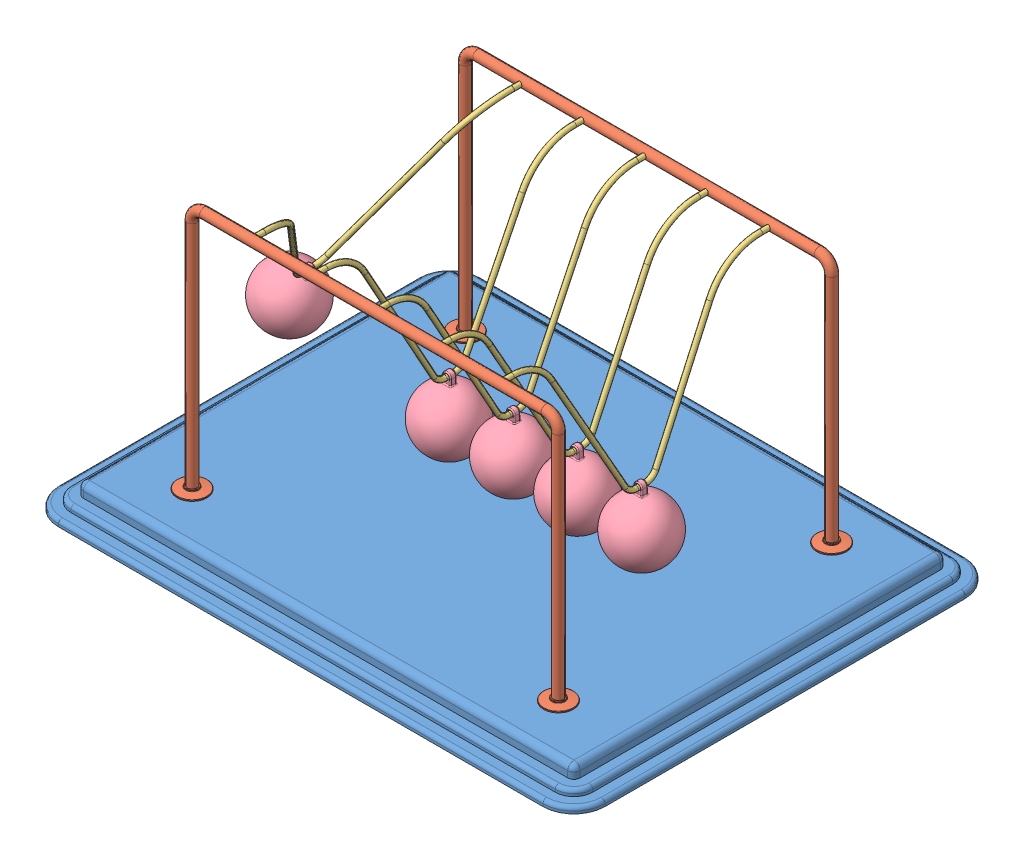
SolidWorks assembly Newtons Cradle NewtonsCradle 0254, configuration Default. Lengths in mm.
Overall size (440 222 340).
13 component instances, 4 part files, 34 mates.
Components (placement in the parent):
- Base 205,834683954619-1: Base 205,834683954619 [Default] at (-16.2968 -4.1587 11.425) size (440 20 340)
- frame NewtonsCradle 0254-1: frame NewtonsCradle 0254 [Default] at (-16.2968 144.4547 -98.575) size (319 202 24)
- frame NewtonsCradle 0254-2: frame NewtonsCradle 0254 [Default] at (-16.2968 144.4547 121.425) x (-1 0 0) z (0 0 -1) size (319 202 24)
- Hanging thing NewtonsCradle 0254-1: Hanging thing NewtonsCradle 0254 [Default] at (-157.6326 134.1825 11.425) x (0 0 1) z (-0.859985 0.510319 0) size (220 129 4)
- Hanging thing NewtonsCradle 0254-2: Hanging thing NewtonsCradle 0254 [Default] at (-66.576 122.8418 11.425) x (0 0 1) z (-0.999994 0.003446 0) size (220 129 4)
- Hanging thing NewtonsCradle 0254-3: Hanging thing NewtonsCradle 0254 [Default] at (-15.6923 122.8436 11.425) x (0 0 1) z (-0.999972 -0.007464 0) size (220 129 4)
- Hanging thing NewtonsCradle 0254-4: Hanging thing NewtonsCradle 0254 [Default] at (35.2213 122.8555 11.425) x (0 0 1) z (-0.999824 -0.018742 0) size (220 129 4)
- Hanging thing NewtonsCradle 0254-5: Hanging thing NewtonsCradle 0254 [Default] at (86.0287 122.8747 11.425) x (0 0 1) z (-0.999588 -0.028711 0) size (220 129 4)
- Sphere NewtonsCradle 0254-1: Sphere NewtonsCradle 0254 [Default] at (-195.3962 70.5436 11.425) x (0.859985 -0.510319 0) z (0 0 1) size (50 58.5 50)
- Sphere NewtonsCradle 0254-2: Sphere NewtonsCradle 0254 [Default] at (88.1533 48.9052 11.425) x (0.999588 0.028711 0) z (0 0 1) size (50 58.5 50)
- Sphere NewtonsCradle 0254-3: Sphere NewtonsCradle 0254 [Default] at (-15.14 48.8456 11.425) x (0.999972 0.007464 0) z (0 0 1) size (50 58.5 50)
- Sphere NewtonsCradle 0254-4: Sphere NewtonsCradle 0254 [Default] at (36.6081 48.8685 11.425) x (0.999824 0.018742 0) z (0 0 1) size (50 58.5 50)
- Sphere NewtonsCradle 0254-5: Sphere NewtonsCradle 0254 [Default] at (-66.831 48.8422 11.425) x (0.999994 -0.003446 0) z (0 0 1) size (50 58.5 50)
Mates (geometry in assembly coordinates):
- Coincident1: coincident anti-aligned: plane of Base-1 through (-211.2968 5.8413 156.425) normal (0 1 0); plane of frame-2 through (-175.7968 5.8413 121.425) normal (0 -1 0)
- Coincident2: coincident anti-aligned: plane of Base-1 through (-211.2968 5.8413 156.425) normal (0 1 0); plane of frame-1 through (143.2032 5.8413 -98.575) normal (0 -1 0)
- Concentric1: concentric anti-aligned: cylinder of frame-1 through (-116.2968 203.8413 -94.575) axis (0 0 -1) radius 2; cylinder of frame-2 through (-116.2968 203.8413 117.425) axis (0 0 1) radius 2
- Concentric2: concentric anti-aligned: cylinder of frame-1 through (83.7032 203.8413 -94.575) axis (0 0 -1) radius 2; cylinder of frame-2 through (83.7032 203.8413 117.425) axis (0 0 1) radius 2
- Distance1: distance = 60 mm: plane of frame-1 through (-16.2968 144.4547 -98.575) normal (0 0 1); line of Base-1 through (-211.2968 -12.1587 -158.575) axis (1 0 0)
- Distance2: distance = 60 mm: line of Base-1 through (178.7032 -12.1587 181.425) axis (-1 0 0); plane of frame-2 through (-16.2968 144.4547 121.425) normal (0 0 -1)
- Distance3: distance = 220 mm: plane of frame-2 through (-16.2968 144.4547 121.425) normal (-1 0 0); line of Base-1 through (-236.2968 -12.1587 156.425) axis (0 0 -1)
- Concentric3: concentric anti-aligned: cylinder of frame-1 through (-116.2968 203.8413 -94.575) axis (0 0 -1) radius 2; cylinder of Hanging thing-1 through (-116.2968 203.8413 111.425) axis (0 0 1) radius 2
- Concentric4: concentric anti-aligned: cylinder of frame-1 through (-116.2968 203.8413 -94.575) axis (0 0 -1) radius 2; cylinder of Hanging thing-1 through (-116.2968 203.8413 -98.575) axis (0 0 1) radius 2
- Concentric5: concentric aligned: cylinder of frame-2 through (-66.2968 203.8413 117.425) axis (0 0 1) radius 2; cylinder of Hanging thing-2 through (-66.2968 203.8413 111.425) axis (0 0 1) radius 2
- Concentric6: concentric aligned: cylinder of frame-2 through (-16.2968 203.8413 117.425) axis (0 0 1) radius 2; cylinder of Hanging thing-3 through (-16.2968 203.8413 111.425) axis (0 0 1) radius 2
- Concentric7: concentric aligned: cylinder of frame-2 through (33.7032 203.8413 117.425) axis (0 0 1) radius 2; cylinder of Hanging thing-4 through (33.7032 203.8413 111.425) axis (0 0 1) radius 2
- Concentric8: concentric aligned: cylinder of frame-2 through (83.7032 203.8413 117.425) axis (0 0 1) radius 2; cylinder of Hanging thing-5 through (83.7032 203.8413 111.425) axis (0 0 1) radius 2
- Coincident5: coincident anti-aligned: plane of frame-2 through (83.7032 203.8413 121.425) normal (0 0 -1); plane of Hanging thing-5 through (83.7032 203.8413 121.425) normal (0 0 1)
- Coincident6: coincident anti-aligned: plane of frame-2 through (33.7032 203.8413 121.425) normal (0 0 -1); plane of Hanging thing-4 through (33.7032 203.8413 121.425) normal (0 0 1)
- Coincident7: coincident anti-aligned: plane of frame-2 through (-16.2968 203.8413 121.425) normal (0 0 -1); plane of Hanging thing-3 through (-16.2968 203.8413 121.425) normal (0 0 1)
- Coincident8: coincident anti-aligned: plane of frame-2 through (-66.2968 203.8413 121.425) normal (0 0 -1); plane of Hanging thing-2 through (-66.2968 203.8413 121.425) normal (0 0 1)
- Coincident9: coincident anti-aligned: plane of frame-2 through (-116.2968 203.8413 121.425) normal (0 0 -1); plane of Hanging thing-1 through (-116.2968 203.8413 121.425) normal (0 0 1)
- Concentric9: concentric anti-aligned: cylinder of Hanging thing-1 through (-117.0163 78.8434 7.925) axis (0 0 1) radius 2; cylinder of Sphere-1 through (-117.0163 78.8434 13.925) axis (0 0 -1) radius 2
- Concentric13: concentric anti-aligned: cylinder of Hanging thing-2 through (-66.7276 78.842 7.925) axis (0 0 1) radius 2; cylinder of Sphere-5 through (-66.7276 78.842 13.925) axis (0 0 -1) radius 2
- Concentric15: concentric anti-aligned: cylinder of Hanging thing-3 through (-15.3639 78.8448 7.925) axis (0 0 1) radius 2; cylinder of Sphere-3 through (-15.3639 78.8448 13.925) axis (0 0 -1) radius 2
- Concentric16: concentric anti-aligned: cylinder of Hanging thing-5 through (87.292 78.8928 7.925) axis (0 0 1) radius 2; cylinder of Sphere-2 through (87.292 78.8928 13.925) axis (0 0 -1) radius 2
- Concentric17: concentric anti-aligned: cylinder of Hanging thing-4 through (36.0459 78.8632 7.925) axis (0 0 1) radius 2; cylinder of Sphere-4 through (36.0459 78.8632 13.925) axis (0 0 -1) radius 2
- Parallel1: parallel anti-aligned: plane of Hanging thing-1; plane of Sphere-1
- Coincident22: coincident anti-aligned: plane of Hanging thing-1; plane of Sphere-1
- Coincident12: coincident aligned: plane of Hanging thing-2 through (-66.576 122.8418 11.425) normal (0 0 1); plane of Sphere-5 through (-66.831 48.8422 11.425) normal (0 0 1)
- Coincident10: coincident aligned: plane of Hanging thing-1 through (-116.763 122.8426 11.425) normal (0 0 1); plane of Sphere-1 through (-118.5806 48.8842 11.425) normal (0 0 1)
- Coincident13: coincident anti-aligned: plane of Hanging thing-2 through (-66.576 122.8418 11.425) normal (-0.999994 0.003446 0); plane of Sphere-5 through (-66.831 48.8422 11.425) normal (0.999994 -0.003446 0)
- Coincident14: coincident anti-aligned: plane of Hanging thing-3 through (-15.6923 122.8436 11.425) normal (-0.999972 -0.007464 0); plane of Sphere-3 through (-15.14 48.8456 11.425) normal (0.999972 0.007464 0)
- Coincident15: coincident aligned: plane of Hanging thing-3 through (-15.6923 122.8436 11.425) normal (0 0 1); plane of Sphere-3 through (-15.14 48.8456 11.425) normal (0 0 1)
- Coincident18: coincident aligned: plane of Hanging thing-4 through (35.2213 122.8555 11.425) normal (0 0 1); plane of Sphere-4 through (36.6081 48.8685 11.425) normal (0 0 1)
- Coincident19: coincident anti-aligned: plane of Hanging thing-4 through (35.2213 122.8555 11.425) normal (-0.999824 -0.018742 0); plane of Sphere-4 through (36.6081 48.8685 11.425) normal (0.999824 0.018742 0)
- Coincident20: coincident anti-aligned: plane of Hanging thing-5 through (86.0287 122.8747 11.425) normal (-0.999588 -0.028711 0); plane of Sphere-2 through (88.1533 48.9052 11.425) normal (0.999588 0.028711 0)
- Coincident21: coincident aligned: plane of Hanging thing-5 through (86.0287 122.8747 11.425) normal (0 0 1); plane of Sphere-2 through (88.1533 48.9052 11.425) normal (0 0 1)
